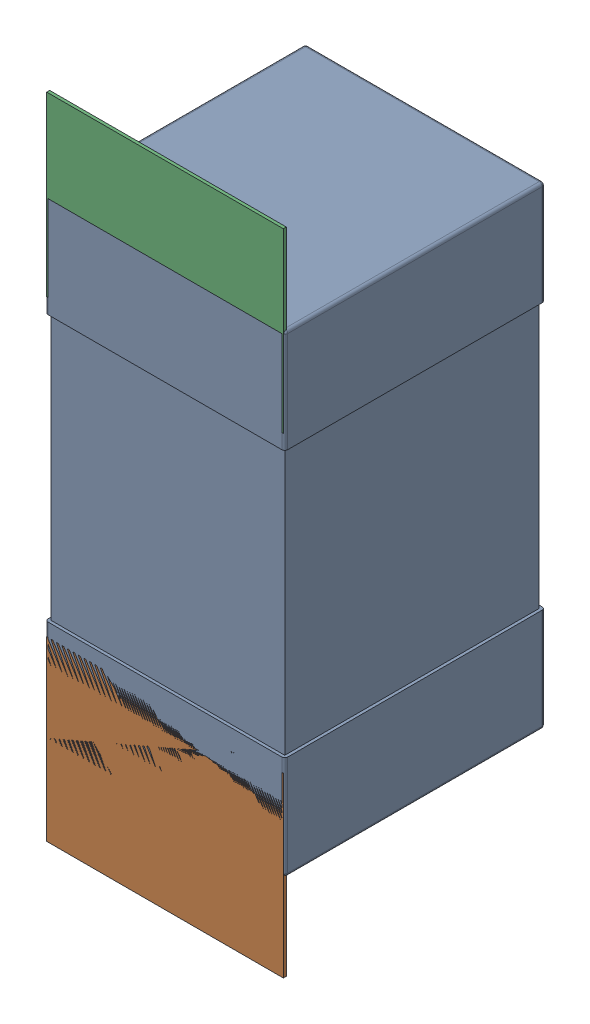
SolidWorks assembly C109, configuration Défaut. Lengths in mm.
Overall size (0.81 2.19 0.88).
5 component instances, 2 part files, 0 mates.
Components (placement in the parent):
- 0603_C-1: 0603_C [Défaut] at (8.6208 -9.4544 -2.0818) x (0 1 0) z (0 0 -1) size (1.6 0.81 0.88)
- 8260087904-1: 8260087904 [Défaut] at (8.6208 -9.7993 -2.0918) size (0.8 0.6 0.01)
  - Extruded_1211-1: Extruded_1211 [Défaut] at origin size (0.8 0.6 0.01)
- 8260087904-2: 8260087904 [Défaut] at (8.6208 -8.2044 -2.0918) size (0.8 0.6 0.01)
  - Extruded_1211-1: Extruded_1211 [Défaut] at origin size (0.8 0.6 0.01)
